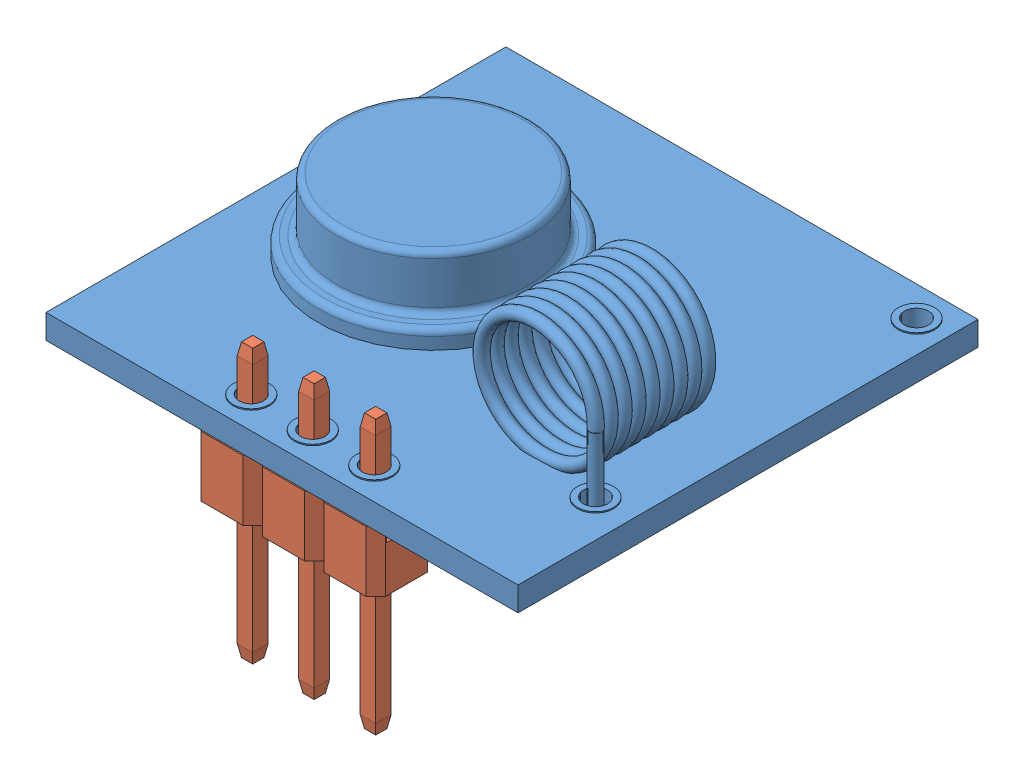
SolidWorks assembly assembly, configuration Default. Lengths in mm.
Overall size (19.5 15.32 19).
2 component instances, 2 part files, 3 mates.
Components (placement in the parent):
- pcb-1: pcb [Default] at (-5.2162 8.4542 22.7312) size (19.5 7.02 19)
- header-1: header [Default] at (7.381 8.5109 22.0051) x (-1 0 0) z (0 0 1) size (7.62 11.3 2.54)
Mates (geometry in assembly coordinates):
- Coincident1: coincident anti-aligned: plane of pcb-1 through (7.0738 8.4042 21.4612) normal (0 -1 0); plane of header-1 through (7.1338 8.2975 21.4612) normal (0 1 0)
- Coincident2: coincident: plane of pcb-1 through (-5.2162 9.4542 22.7312) normal (0 0 1); plane of header-1 through (8.0038 5.7975 22.7312) normal (0 0 1)
- Distance1: distance = 6 mm: plane of header-1 through (0.7838 5.9042 20.5912) normal (-1 0 0); plane of pcb-1 through (-5.2162 9.4542 22.7312) normal (-1 0 0)
